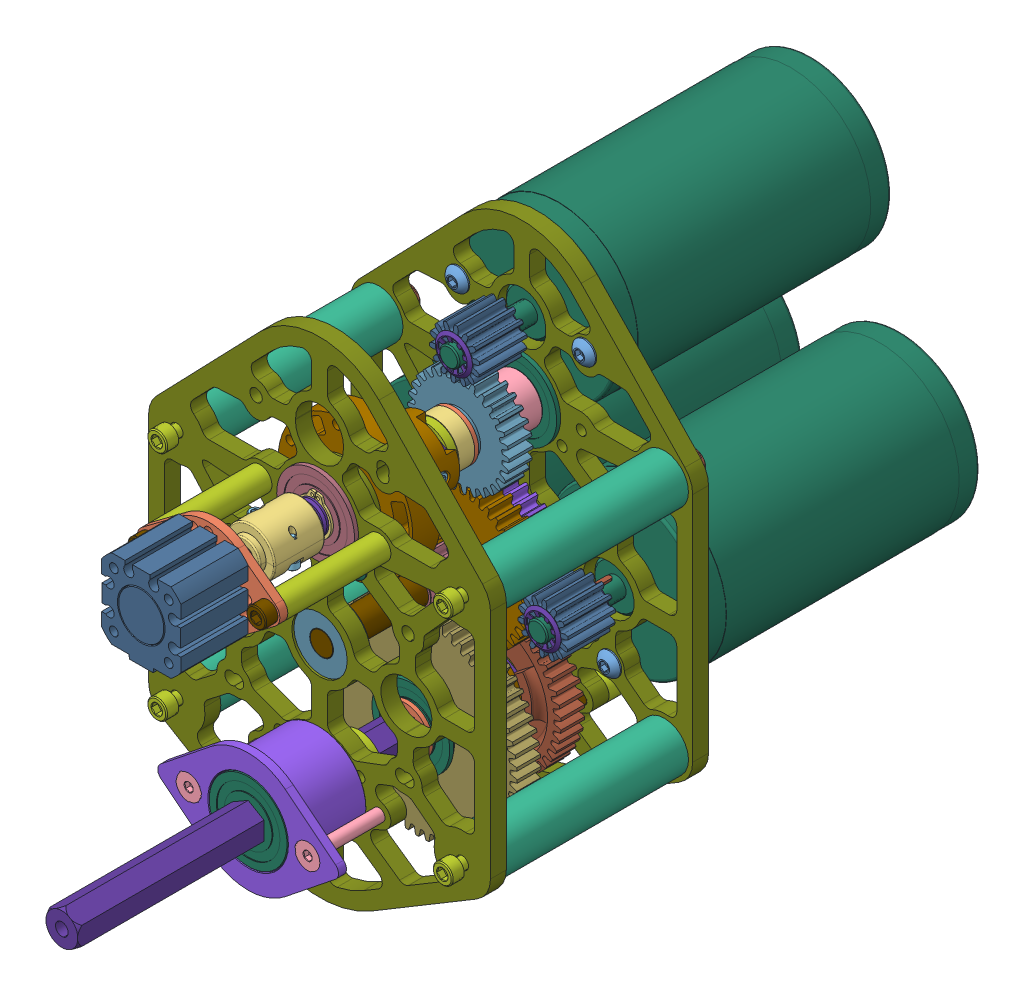
SolidWorks assembly 217-3433-PTO Config STEP, configuration Default. Lengths in mm.
Overall size (140.54 205.19 305.07).
116 component instances, 47 part files, 0 mates.
Components (placement in the parent):
- 217-2428-027 Rev1_97414A630-1: 217-2428-027 Rev1_97414A630 [Default] at (0 -47.0408 -31.6122) x (0 0 1) z (-1 0 0) size (0.64 5.89 7.9)
- 217-3423-005 Rev1-1: 217-3423-005 Rev1 [Default] at (0 -47.0408 -46.0375) size (57.15 38.1 3.17)
- 217-3195-200 Rev1-1: 217-3195-200 Rev1 [Default] at (0 -47.0408 -35.3587) x (-1 0 0) z (0 0 -1) size (20.44 19.56 22.71)
  - 217-3195-010 Rev1-1: 217-3195-010 Rev1 [Default] x (-1 0 0) z (0 0 1) size (19.61 11.78 22.71)
  - 217-3195-010 Rev1-2: 217-3195-010 Rev1 [Default] at origin size (19.61 11.78 22.71)
  - 217-2778-NCQ8A075-050M_1032_Nut_90545A111-1: 217-2778-NCQ8A075-050M_1032_Nut_90545A111 [Default] at (0 0 2.5527) x (-0.5 0.866025 0) z (0 0 1) size (9.53 11 3.39)
  - 91251A107_91251A107-1: 91251A107_91251A107 [Default] at (-7.4168 -4.9375 -0.635) x (1 0 0) z (0 -1 0) size (4.65 4.65 10.79)
  - 91251A107_91251A107-2: 91251A107_91251A107 [Default] at (7.4168 4.9375 -0.635) x (-0.837169 0 -0.546944) z (0 1 0) size (4.65 4.65 10.79)
- 217-3489-1: 217-3489 [Default] at (0 -47.0408 -28.9135) x (0 0 -1) z (0.779786 -0.626046 0) size (4.77 12.7 12.7)
- 217-2428-027 Rev1_97414A630-2: 217-2428-027 Rev1_97414A630 [Default] at (0 45.7708 99.4031) x (0 0 1) z (-0.998671 -0.051538 0) size (0.64 5.89 7.9)
- 217-3195-200 Rev1-2: 217-3195-200 Rev1 [Default] at (0 45.7708 103.048) x (-1 0 0) z (0 0 1) size (20.44 19.56 22.71)
  - 217-3195-010 Rev1-1: 217-3195-010 Rev1 [Default] x (-1 0 0) z (0 0 1) size (19.61 11.78 22.71)
  - 217-3195-010 Rev1-2: 217-3195-010 Rev1 [Default] at origin size (19.61 11.78 22.71)
  - 217-2778-NCQ8A075-050M_1032_Nut_90545A111-1: 217-2778-NCQ8A075-050M_1032_Nut_90545A111 [Default] at (0 0 2.5527) x (-0.5 0.866025 0) z (0 0 1) size (9.53 11 3.39)
  - 91251A107_91251A107-1: 91251A107_91251A107 [Default] at (-7.4168 -4.9375 -0.635) x (1 0 0) z (0 -1 0) size (4.65 4.65 10.79)
  - 91251A107_91251A107-2: 91251A107_91251A107 [Default] at (7.4168 4.9375 -0.635) x (-0.837169 0 -0.546944) z (0 1 0) size (4.65 4.65 10.79)
- 217-3489-2: 217-3489 [Default] at (0 45.7708 96.6028) x (0 0 -1) z (-0.103791 0.994599 0) size (4.77 12.7 12.7)
- 217-3423-005 Rev1-2: 217-3423-005 Rev1 [Default] at (0 45.7708 127) size (57.15 38.1 3.17)
- 217-3423-006 Rev1-1: 217-3423-006 Rev1 [Default] at (-23.8125 -47.0408 -23.8125) x (0 0 1) z (-0.878816 -0.477161 0) size (41.27 9.53 9.53)
- 217-3423-006 Rev1-2: 217-3423-006 Rev1 [Default] at (23.8125 -47.0408 -23.8125) x (0 0 1) z (-1 0 0) size (41.27 9.53 9.53)
- 217-3423-008 Rev1-1: 217-3423-008 Rev1 [Default] at (0 -47.0408 -24.043) x (0 1 0) z (0 0 1) size (7.14 7.14 57.15)
- 217-3423-008 Rev1-2: 217-3423-008 Rev1 [Default] at (0 45.7708 91.7323) x (0 -1 0) z (0 0 -1) size (7.14 7.14 57.15)
- 217-3423-009 Rev1-1: 217-3423-009 Rev1 [Default] at (0 -47.0408 19.5624) x (-1 0 0) z (0 0 1) size (26.99 26.99 13.24)
- 217-3423-009 Rev1-2: 217-3423-009 Rev1 [Default] at (0 45.7708 48.1269) x (-1 0 0) z (0 0 1) size (26.99 26.99 13.24)
- 217-2778-001 Rev2_NCQ8A075-050M-1: 217-2778-001 Rev2_NCQ8A075-050M [Default] at (0 45.7708 142.0495) x (1 0 0) z (0 0 -1) size (31.75 33.34 53.29)
  - 217-2778-NCQ8A075-050M_NCQ8 Tube_075A-1: 217-2778-NCQ8A075-050M_NCQ8 Tube_075A [Default] at origin size (31.75 33.34 26.92)
  - 217-2778-NCQ8A075-050M_NCQ8 Rod_075M-1: 217-2778-NCQ8A075-050M_NCQ8 Rod_075M [Default] at (0 0 4.561) x (-1 0 0) z (0 0 1) size (18.95 18.95 35.27)
  - 217-2778-NCQ8A075-050M_Snap Ring_075-1: 217-2778-NCQ8A075-050M_Snap Ring_075 [Default] at (0 0 10.362) size (21 20.74 0.97)
- 217-2778-001 Rev2_NCQ8A075-050M-2: 217-2778-001 Rev2_NCQ8A075-050M [Default] at (0 -47.0408 -61.087) x (-1 0 0) z (0 0 1) size (31.75 33.34 53.29)
  - 217-2778-NCQ8A075-050M_NCQ8 Tube_075A-1: 217-2778-NCQ8A075-050M_NCQ8 Tube_075A [Default] at origin size (31.75 33.34 26.92)
  - 217-2778-NCQ8A075-050M_NCQ8 Rod_075M-1: 217-2778-NCQ8A075-050M_NCQ8 Rod_075M [Default] at (0 0 4.561) x (-1 0 0) z (0 0 1) size (18.95 18.95 35.27)
  - 217-2778-NCQ8A075-050M_Snap Ring_075-1: 217-2778-NCQ8A075-050M_Snap Ring_075 [Default] at (0 0 10.362) size (21 20.74 0.97)
- 217-2731-1: 217-2731 [Default] at (0 -47.0408 3.175) x (-0.539745 -0.841828 0) z (0.841828 -0.539745 0) size (31.12 7.94 31.12)
- 217-2731-2: 217-2731 [Default] at (0 45.7708 77.7875) x (0.750662 -0.660687 0) z (-0.660687 -0.750662 0) size (31.12 7.94 31.12)
- 217-2733-1: 217-2733 [Default] at (0 0 4.7625) x (0 0 -1) z (0.79471 -0.606989 0) size (7.11 24.61 24.61)
- 217-2733-2: 217-2733 [Default] at (0 0 76.2) x (0 0 1) z (-0.575096 -0.818086 0) size (7.11 24.61 24.61)
- 217-2734-1: 217-2734 [Default] at (0 -47.0408 104.775) x (0 -1 0) z (-1 0 0) size (31.12 7.94 31.12)
- 217-2734-2: 217-2734 [Default] at (0 45.7708 -3.175) x (-0.32713 0.944979 0) z (0.944979 0.32713 0) size (31.12 7.94 31.12)
- 217-2734-3: 217-2734 [Default] at (0 -47.0408 39.6557) x (-0.32713 0.944979 0) z (0.944979 0.32713 0) size (31.12 7.94 31.12)
- 217-2743-1: 217-2743 [Default] at (0 -47.0408 7.9057) x (0 0 -1) z (0.947967 0.31837 0) size (7.94 28.57 28.57)
- 217-2743-2: 217-2743 [Default] at (0 45.7708 73.025) x (0 0 -1) z (0.939414 -0.342784 0) size (7.94 28.57 28.57)
- 217-2614-002_98430A132-1: 217-2614-002_98430A132 [Default] at (35.4115 -3.81 31.1531) x (0 0 -1) z (-0.444133 -0.895961 0) size (1.2 14.83 14.83)
- 217-2614-002_98430A132-2: 217-2614-002_98430A132 [Default] at (35.4115 -3.81 9.9695) x (0 0 1) z (-0.864814 -0.502092 0) size (1.2 14.83 14.83)
- 217-2614-002_98430A132-3: 217-2614-002_98430A132 [Default] at (-35.4115 -3.81 31.1531) x (0 0 -1) z (-0.867628 -0.497214 0) size (1.2 14.83 14.83)
- 217-2614-002_98430A132-4: 217-2614-002_98430A132 [Default] at (-35.4115 -3.81 9.9695) x (0 0 1) z (-0.989494 0.144574 0) size (1.2 14.83 14.83)
- 217-2614-002_98430A132-5: 217-2614-002_98430A132 [Default] at (0 73.7616 31.1531) x (0 0 -1) z (0.241649 -0.970364 0) size (1.2 14.83 14.83)
- 217-2614-002_98430A132-6: 217-2614-002_98430A132 [Default] at (0 73.7616 9.9695) x (0 0 1) z (-0.864814 -0.502092 0) size (1.2 14.83 14.83)
- 217-3421-007 Rev1-1: 217-3421-007 Rev1 [Default] at (23.8125 45.7708 128.5875) x (0 0 -1) z (0.991978 -0.126413 0) size (55.85 7.92 7.92)
- 217-3421-007 Rev1-2: 217-3421-007 Rev1 [Default] at (-23.8125 45.7708 128.5875) x (0 0 -1) z (0.991978 -0.126413 0) size (55.85 7.92 7.92)
- 217-3421-007 Rev1-3: 217-3421-007 Rev1 [Default] at (23.8125 -47.0408 -47.625) x (0 0 1) z (-0.993182 -0.116573 0) size (55.85 7.92 7.92)
- 217-3421-007 Rev1-4: 217-3421-007 Rev1 [Default] at (-23.8125 -47.0408 -47.625) x (0 0 1) z (-0.993182 -0.116573 0) size (55.85 7.92 7.92)
- 217-3421-009 Rev1-1: 217-3421-009 Rev1 [Default] at (-25.4 73.7616 3.175) x (0 0 -1) z (0.999228 -0.039284 0) size (15.78 9.26 9.25)
- 217-3421-009 Rev1-2: 217-3421-009 Rev1 [Default] at (35.4115 21.59 3.175) x (0 0 -1) z (0.999228 -0.039284 0) size (15.78 9.26 9.25)
- 217-3421-009 Rev1-3: 217-3421-009 Rev1 [Default] at (25.4 73.7616 3.175) x (0 0 -1) z (0.656255 -0.754539 0) size (15.78 9.26 9.25)
- 217-3421-009 Rev1-4: 217-3421-009 Rev1 [Default] at (-35.4115 21.59 3.175) x (0 0 -1) z (0.999228 -0.039284 0) size (15.78 9.26 9.25)
- 217-3421-009 Rev1-5: 217-3421-009 Rev1 [Default] at (-35.4115 -29.21 3.175) x (0 0 -1) z (0.999228 -0.039284 0) size (15.78 9.26 9.25)
- 217-3421-009 Rev1-6: 217-3421-009 Rev1 [Default] at (35.4115 -29.21 3.175) x (0 0 -1) z (0.999228 -0.039284 0) size (15.78 9.26 9.25)
- 217-3421-010 Rev1-1: 217-3421-010 Rev1 [Default] at (57.15 45.7708 -3.175) x (0.017497 0.999847 0) z (-0.999847 0.017497 0) size (9.53 6.13 11)
- 217-3421-010 Rev1-2: 217-3421-010 Rev1 [Default] at (57.15 -47.0408 -3.175) x (0.017497 0.999847 0) z (-0.999847 0.017497 0) size (9.53 6.13 11)
- 217-3421-010 Rev1-3: 217-3421-010 Rev1 [Default] at (-57.15 45.7708 -3.175) x (0.017497 0.999847 0) z (-0.999847 0.017497 0) size (9.53 6.13 11)
- 217-3421-010 Rev1-4: 217-3421-010 Rev1 [Default] at (-57.15 -47.0408 -3.175) x (0.017497 0.999847 0) z (-0.999847 0.017497 0) size (9.53 6.13 11)
- 217-3421-011 Rev2_97633A200-1: 217-3421-011 Rev2_97633A200 [Default] at (0 45.7708 86.1695) x (0 0 1) z (-0.99554 0.094343 0) size (0.89 16.1 14.34)
- 217-3421-011 Rev2_97633A200-2: 217-3421-011 Rev2_97633A200 [Default] at (0 -47.0408 -5.2388) x (0 0 1) z (-0.999986 0.005305 0) size (0.89 16.1 14.34)
- 217-3422-007 Rev1-1: 217-3422-007 Rev1 [Default] at (23.8125 -47.0408 109.4868) x (0 0 1) z (-0.947089 0.320972 0) size (35.11 10.21 10.21)
- 217-3422-007 Rev1-2: 217-3422-007 Rev1 [Default] at (-23.8125 -47.0408 109.4868) x (0 0 1) z (-0.947089 0.320972 0) size (35.11 10.21 10.21)
- 217-3423-014 Rev1-1: 217-3423-014 Rev1 [Default] at (-13.4938 -47.0408 19.5624) x (0 0.998248 0.059168) z (-1 0 0) size (4.65 4.65 26.79)
- 217-3423-014 Rev1-2: 217-3423-014 Rev1 [Default] at (-13.4938 45.7708 48.1269) x (0 -0.673339 -0.739334) z (-1 0 0) size (4.65 4.65 26.79)
- 217-3423-016 Rev1-1: 217-3423-016 Rev1 [Default] at (16.1541 -37.7142 -4.7625) x (0 0 1) z (-0.958364 -0.285548 0) size (11.03 9.26 9.25)
- 217-3423-016 Rev1-2: 217-3423-016 Rev1 [Default] at (-16.1541 -37.7142 -4.7625) x (0 0 1) z (-0.958364 -0.285548 0) size (11.03 9.26 9.25)
- 217-3423-016 Rev1-3: 217-3423-016 Rev1 [Default] at (0 -65.6939 -4.7625) x (0 0 1) z (0.993879 0.110476 0) size (11.03 9.26 9.25)
- 217-3424-003 Rev1-1: 217-3424-003 Rev1 [Default] at (57.15 -47.0408 87.3125) x (0 0 -1) z (0.754419 0.656393 0) size (100.3 7.92 7.92)
- 217-3424-003 Rev1-2: 217-3424-003 Rev1 [Default] at (-57.15 -47.0408 87.3125) x (0 0 -1) z (0.754419 0.656393 0) size (100.3 7.92 7.92)
- 217-3424-003 Rev1-3: 217-3424-003 Rev1 [Default] at (-57.15 45.7708 87.3125) x (0 0 -1) z (0.754419 0.656393 0) size (100.3 7.92 7.92)
- 217-3424-003 Rev1-4: 217-3424-003 Rev1 [Default] at (57.15 45.7708 87.3125) x (0 0 -1) z (0.754419 0.656393 0) size (100.3 7.92 7.92)
- 217-3210-001 Rev1_30t-1: 217-3210-001 Rev1_30t [Default] at (0 0 11.0871) x (0.892842 -0.450371 0) z (0 0 1) size (41.01 41.12 12.65)
- 217-3215-001 Rev1_42t-1: 217-3215-001 Rev1_42t [Default] at (0 0 23.7363) x (-0.743738 0.668471 0) z (0 0 1) size (56.22 56.3 12.65)
- 217-3414-001 Rev1_14t Steel Pinion-1: 217-3414-001 Rev1_14t Steel Pinion [Default] at (-35.4115 -3.81 20.5613) x (0.095909 -0.99539 0) z (0 0 1) size (20.32 20.6 19.05)
- 217-3414-001 Rev1_14t Steel Pinion-2: 217-3414-001 Rev1_14t Steel Pinion [Default] at (35.4115 -3.81 20.5613) x (-0.277698 -0.960668 0) z (0 0 1) size (20.32 20.6 19.05)
- 217-3414-001 Rev1_14t Steel Pinion-3: 217-3414-001 Rev1_14t Steel Pinion [Default] at (0 73.7616 20.5613) x (-0.277698 -0.960668 0) z (0 0 1) size (20.32 20.6 19.05)
- 217-3418-001 Rev2_44t-1: 217-3418-001 Rev2_44t [Default] at (0 -47.0408 11.922) x (0.76226 0.647271 0) z (0 0 1) size (58.67 58.67 9.53)
- 217-3420-001 Rev2_60t-1: 217-3420-001 Rev2_60t [Default] at (0 -47.0408 39.6082) x (-0.373856 -0.927487 0) z (0 0 -1) size (78.95 78.95 9.53)
- 217-3100-001_14t-1: 217-3100-001_14t [Default] at (0 0 39.6875) x (0.998696 0.051045 0) z (0 0 1) size (20.67 20.95 12.7)
- 217-2705-001_30t-1: 217-2705-001_30t [Default] at (0 45.7708 23.7871) x (0.993036 0.117815 0) z (0 0 1) size (41.01 41.12 12.65)
- 217-2000-1: 217-2000 [Default] at (35.4115 -3.81 -3.175) x (0 0 -1) z (1 0 0) size (150.2 64.01 64.01)
- 217-2000-2: 217-2000 [Default] at (-35.4115 -3.81 -3.175) x (0 0 -1) z (1 0 0) size (150.2 64.01 64.01)
- 217-2000-3: 217-2000 [Default] at (0 73.7616 -3.175) x (0 0 -1) z (0 1 0) size (150.2 64.01 64.01)
- 217-3433-001 Rev1_Default_As Machined_-1: 217-3433-001 Rev1_Default_As Machined_ [Default] at origin size (136.86 194.46 6.35)
- 217-3433-001 Rev1_Default_As Machined_-2: 217-3433-001 Rev1_Default_As Machined_ [Default] at (0 0 80.9625) x (-1 0 0) z (0 0 -1) size (136.86 194.46 6.35)
- 217-3423-003 Rev1-1: 217-3423-003 Rev1 [Default] at (0 -47.0408 25.7651) x (0 -1 0) z (0 0 1) size (18.33 15.88 194.69)
- 217-3423-003 Rev1-2: 217-3423-003 Rev1 [Default] at (0 45.7708 55.1656) x (0 1 0) z (0 0 -1) size (18.33 15.88 194.69)
- 217-3424-005 Rev1-1: 217-3424-005 Rev1 [Default] at (0 0 40.4813) x (0 -1 0) z (0 0 1) size (11.11 11.11 85.72)
- 217-3256-001 Rev1-1: 217-3256-001 Rev1 [Default] at (0 0 31.6484) size (15.88 15.88 3.17)
- 217-3257-001 Rev1-1: 217-3257-001 Rev1 [Default] at (0 45.7708 30.9563) size (19.5 19.5 1.59)
- 217-3257-001 Rev1-2: 217-3257-001 Rev1 [Default] at (0 -47.0408 49.1298) size (19.5 19.5 1.59)
- 217-3259-001 Rev1-1: 217-3259-001 Rev1 [Default] at (0 45.7708 34.925) x (0.995688 -0.092763 0) z (0 0 1) size (19.5 19.5 6.35)
- 217-3261-001 Rev1-1: 217-3261-001 Rev1 [Default] at (0 45.7708 11.1125) size (19.5 19.5 12.7)
- 217-3423-004 Rev1-1: 217-3423-004 Rev1 [Default] at (0 -47.0408 3.556) size (19.05 19.05 0.76)
- 217-3423-006 Rev1-3: 217-3423-006 Rev1 [Default] at (-23.8125 45.7708 104.775) x (0 0 1) z (-1 0 0) size (41.27 9.53 9.53)
- 217-3423-006 Rev1-4: 217-3423-006 Rev1 [Default] at (23.8125 45.7708 104.775) x (0 0 1) z (-1 0 0) size (41.27 9.53 9.53)
- 217-3424-002 Rev1-1: 217-3424-002 Rev1 [Default] at (-57.15 -47.0408 40.4813) size (19.13 19.13 80.96)
- 217-3424-002 Rev1-2: 217-3424-002 Rev1 [Default] at (57.15 -47.0408 40.4813) x (0.857249 -0.514902 0) z (0 0 1) size (19.13 19.13 80.96)
- 217-3424-002 Rev1-3: 217-3424-002 Rev1 [Default] at (-57.15 45.7708 40.4813) x (0.857249 -0.514902 0) z (0 0 1) size (19.13 19.13 80.96)
- 217-3424-002 Rev1-4: 217-3424-002 Rev1 [Default] at (57.15 45.7708 40.4813) x (0.982113 0.18829 0) z (0 0 1) size (19.13 19.13 80.96)
- 217-2758-001 Rev1-1: 217-2758-001 Rev1 [Default] at (0 45.7708 39.6875) x (0.999998 -0.001993 0) z (0 0 1) size (19.05 19.05 3.17)
- 217-3422-004 Rev2-1: 217-3422-004 Rev2 [Default] at (0 -47.0408 111.125) size (72.39 47.62 34.67)
- 217-3433-002 Rev1-1: 217-3433-002 Rev1 [Default] at (0 45.7708 69.0087) x (0.144045 -0.989571 0) z (0 0 -1) size (53.98 53.98 14.29)
- 217-3263-001 Rev1-1: 217-3263-001 Rev1 [Default] at (0 -47.0408 92.075) x (0.964295 0.26483 0) z (0 0 1) size (19.5 19.5 25.4)
- 217-3259-001 Rev1-2: 217-3259-001 Rev1 [Default] at (0 -47.0408 76.2) size (19.5 19.5 6.35)
- 217-2758-001 Rev1-2: 217-2758-001 Rev1 [Default] at (0 -47.0408 69.85) x (0.99994 -0.010919 0) z (0 0 1) size (19.05 19.05 3.17)
- 217-2761-001 rev1-1: 217-2761-001 rev1 [Default] at (35.4115 -0.01 12.925) size (2 2 20)
- 217-2761-001 rev1-2: 217-2761-001 rev1 [Default] at (-35.4115 -0.01 12.925) size (2 2 20)
- 217-2761-001 rev1-3: 217-2761-001 rev1 [Default] at (-3.8 73.7616 12.925) x (0 1 0) z (0 0 1) size (2 2 20)
- 217-3423-004 Rev1-2: 217-3423-004 Rev1 [Default] at (0 45.7708 77.3748) size (19.05 19.05 0.76)
- 217-3423-016 Rev1-4: 217-3423-016 Rev1 [Default] at (-16.1541 36.4442 85.725) x (0 0 -1) z (1 0 0) size (11.03 9.26 9.25)
- 217-3423-016 Rev1-5: 217-3423-016 Rev1 [Default] at (16.1541 36.4442 85.725) x (0 0 -1) z (1 0 0) size (11.03 9.26 9.25)
- 217-3257-001 Rev1-3: 217-3257-001 Rev1 [Default] at (0 -47.0408 72.2313) size (19.5 19.5 1.59)
